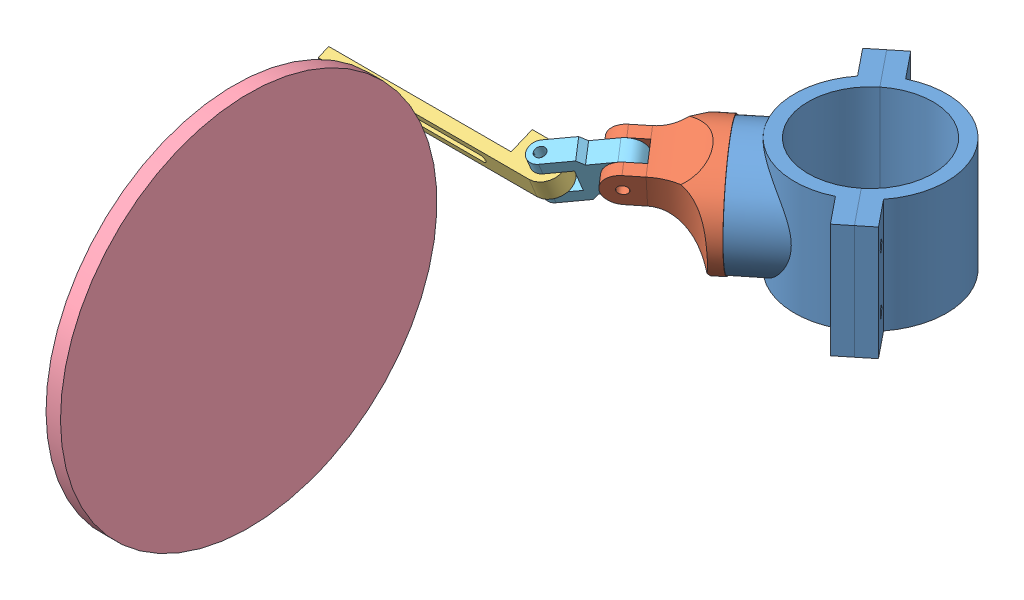
SolidWorks assembly Assem1, configuration Default. Lengths in mm.
Overall size (224.9 215.63 317.79).
5 component instances, 5 part files, 11 mates.
Components (placement in the parent):
- Clamp-1: Clamp [Default] x (0.777671 0 -0.628672) z (0.628672 0 0.777671) size (76.7 50 94.99)
- rotator link-1: rotator link [Default] at (-33.712 25 27.2529) x (0.193378 0.951517 0.239209) z (0.598192 -0.307597 0.739967) size (50.8 40 50.9)
- slotted arm-1: slotted arm [Default] at (-169.1029 26.0387 65.0653) x (1 0 0) z (0 -0.923397 -0.383847) size (100 15 9)
- flywheel-1: flywheel [Default] at (-127 0 152.0746) x (0 0.381849 -0.924225) z (0 -0.924225 -0.381849) size (165.1 6.35 165.1)
- knuckle-1: knuckle [Default] at (-67.424 42.9844 55.5626) x (0 -0.923397 -0.383847) z (0.598192 -0.307597 0.739967) size (20 37.25 9.5)
Mates (geometry in assembly coordinates):
- Concentric1: concentric anti-aligned: cylinder of Clamp-1 through (25.9353 25 -20.9662) axis (-0.777671 0 0.628672) radius 2.25; cylinder of rotator link-1 through (-53.1538 25 42.9697) axis (0.777671 0 -0.628672) radius 2.25
- Coincident4: coincident anti-aligned: plane of Clamp-1 through (-33.712 0 27.2529) normal (-0.777671 0 0.628672); plane of rotator link-1 through (-33.712 25 27.2529) normal (0.777671 0 -0.628672)
- Concentric3: concentric anti-aligned: circle of Clamp-1
- Concentric4: concentric aligned: cylinder of flywheel-1 through (-120.65 0 152.0746) axis (-1 0 0) radius 82.55
- Coincident9: coincident: plane of flywheel-1 through (-127 0 152.0746) normal (-1 0 0)
- Concentric5: concentric aligned: cylinder of rotator link-1 through (-41.375 29.081 69.47) axis (-0.598192 0.307597 -0.739967) radius 2.25; cylinder of knuckle-1 through (-53.7277 35.4329 54.1897) axis (-0.598192 0.307597 -0.739967) radius 2.25
- Width1: width aligned: plane of knuckle-1 through (-59.4105 38.355 47.16) normal (-0.598192 0.307597 -0.739967); plane of rotator link-1 through (-53.7277 35.4329 54.1897) normal (0.598192 -0.307597 0.739967); plane of knuckle-1 through (-55.2242 -0.6296 40.4087) normal (-0.598192 0.307597 -0.739967); plane of rotator link-1 through (-60.907 2.2926 33.379) normal (0.598192 -0.307597 0.739967)
- Width2: width anti-aligned: plane of slotted arm-1 through (-169.1029 32.43 73.1369) normal (0 0.923397 0.383847); plane of knuckle-1 through (-169.1029 24.1195 69.6822) normal (0 -0.923397 -0.383847); plane of slotted arm-1 through (-83.2508 36.141 65.5122) normal (0 -0.923397 -0.383847); plane of knuckle-1 through (-83.2508 26.907 61.6738) normal (0 0.923397 0.383847)
- Concentric6: concentric anti-aligned: cylinder of slotted arm-1 through (-76.6029 26.0749 62.3729) axis (0 0.923397 0.383847) radius 2.25; cylinder of knuckle-1 through (-76.6029 40.3876 68.3226) axis (0 -0.923397 -0.383847) radius 2.25
- Coincident10: coincident anti-aligned: plane of Clamp-1 through (0 0 0) normal (0 -1 0)
- Parallel1: parallel aligned: line of slotted arm-1 through (-76.6029 32.43 73.1369) axis (-1 0 0)
